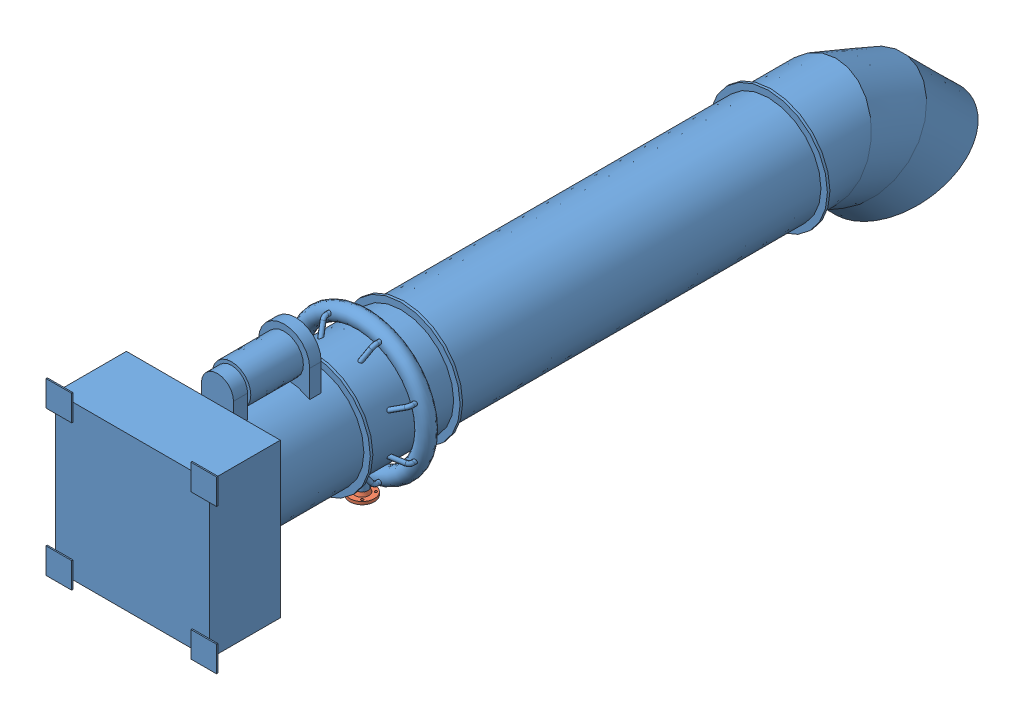
SolidWorks assembly Evaporizer, configuration Default. Lengths in mm.
Overall size (1330 1459.16 6470.69).
2 component instances, 2 part files, 2 mates.
Components (placement in the parent):
- Evaporizer-1: Evaporizer [Default] at (-2140.3277 -202.2128 1266.8021) size (1330 1459.15 6470.69)
- welding neck flange-2: welding neck flange [WNeck Flange 150-NPS3] at (-1540.3277 -890.6888 28.8021) x (1 0 0) z (0 -1 0) size (190.5 190.5 79.86)
Mates (geometry in assembly coordinates):
- Concentric21: concentric aligned: cylinder of Evaporizer-1 through (-1540.3277 -202.2128 28.8021) axis (0 1 0) radius 41; cylinder of welding neck flange-2 through (-1540.3277 -892.2128 28.8021) axis (0 1 0) radius 53.975
- Coincident21: coincident aligned: plane of Evaporizer-1 through (-1540.3277 -892.2128 -16.1979) normal (0 -1 0); plane of welding neck flange-2 through (-1540.3277 -892.2128 28.8021) normal (0 -1 0)
